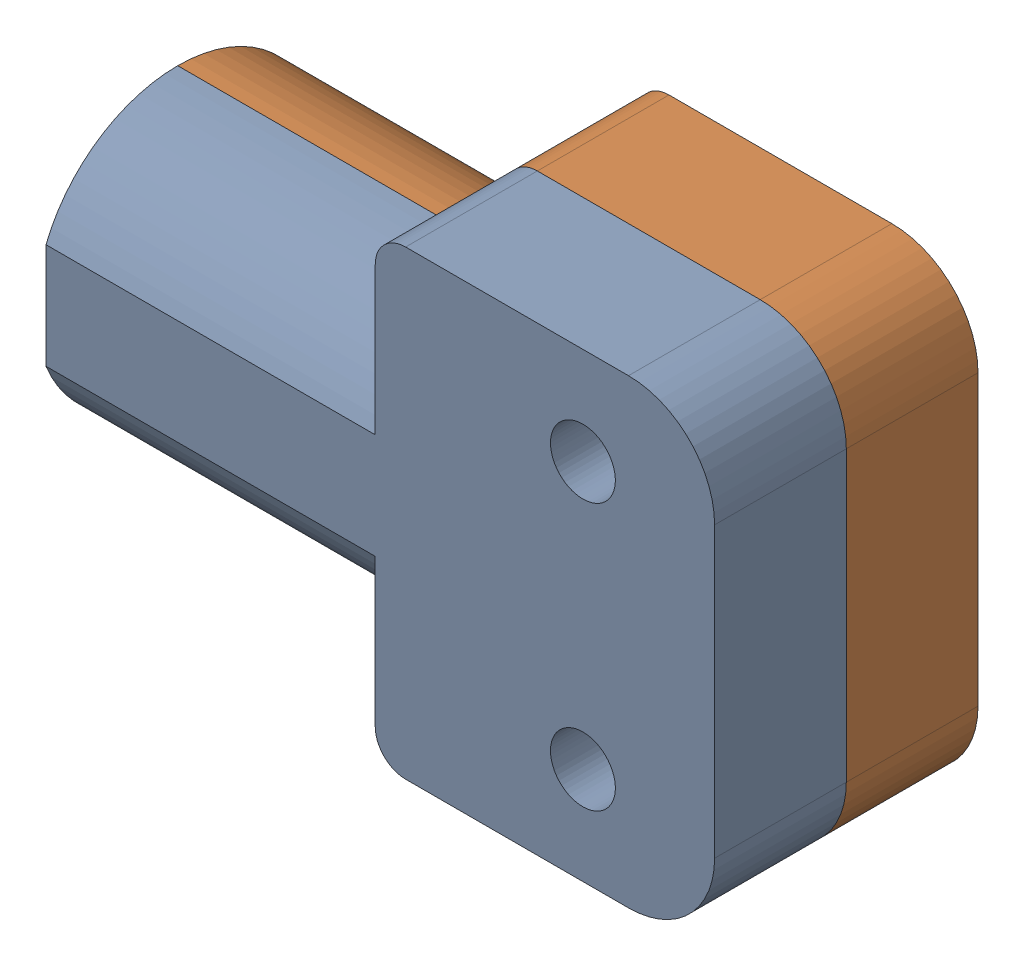
SolidWorks assembly MFG CW Pedal Mount Block Assembly, configuration Default. Lengths in mm.
Overall size (66 45.5 26).
4 component instances, 3 part files, 0 mates.
Components (placement in the parent):
- MFG CW Pedal Mount Block Upper-1: MFG CW Pedal Mount Block Upper [Default] at origin size (66 45.5 13)
- MFG CW Pedal Mount Block Lower-1: MFG CW Pedal Mount Block Lower [Default] at origin size (66 45.5 13)
- M6 x 1 Hex Nut-1: M6 x 1 Hex Nut [Default] at (177 95.845 88.6) size (10 11.55 5)
- M6 x 1 Hex Nut-2: M6 x 1 Hex Nut [Default] at (177 122.155 88.6) size (10 11.55 5)
